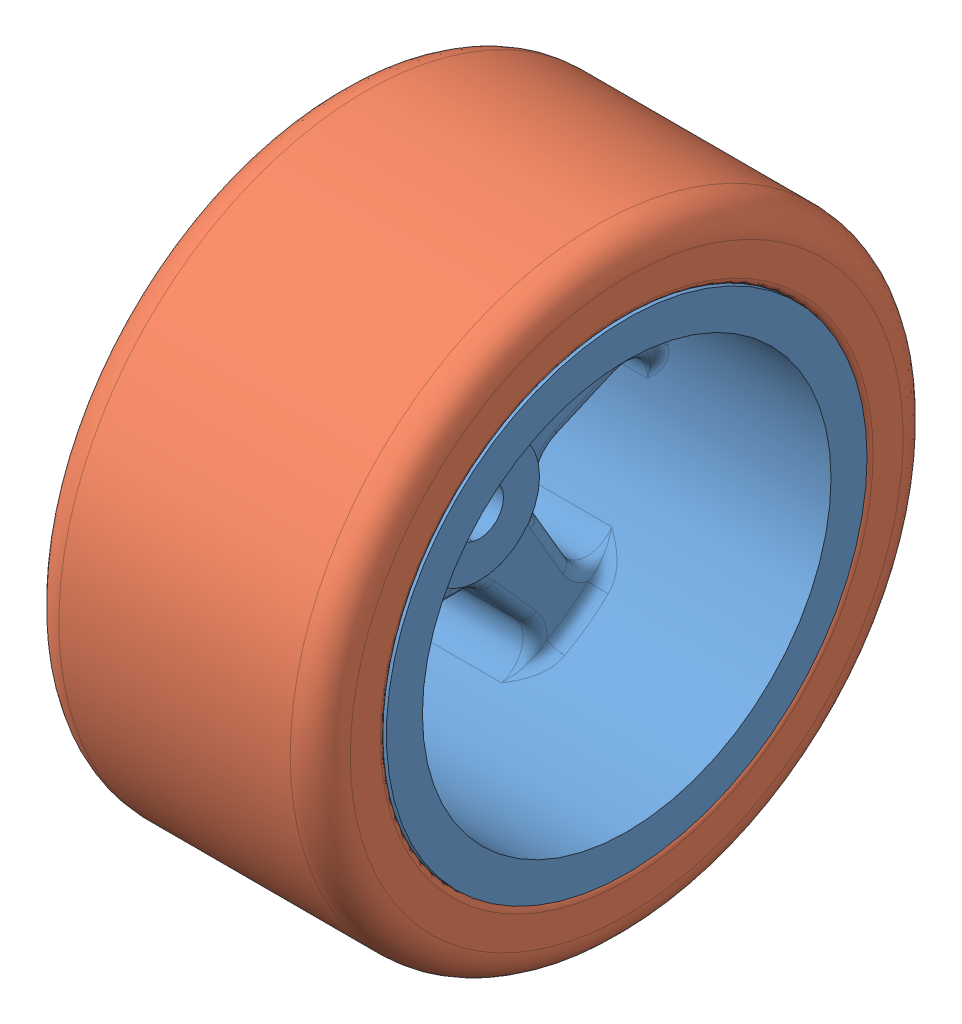
SolidWorks assembly _chassis_wheel_front, configuration Default. Lengths in mm.
Overall size (24.25 51 51).
2 component instances, 2 part files, 2 mates.
Components (placement in the parent):
- chassis_wheel_center_front-1: chassis_wheel_center_front [Default] at (5.9936 1.7491 -4.3511) size (24.25 40 40)
- chassis_tire-1: chassis_tire [Default] at (18.1186 1.7491 -4.3511) size (24.25 51 51)
Mates (geometry in assembly coordinates):
- Concentric1: concentric anti-aligned: cylinder of chassis_wheel_center_front-1 through (17.9936 1.7491 -4.3511) axis (1 0 0) radius 19; cylinder of chassis_tire-1 through (18.1186 1.7491 -4.3511) axis (-1 0 0) radius 19
- Coincident1: coincident anti-aligned: plane of chassis_wheel_center_front-1 through (28.2436 1.7491 -24.3511) normal (-1 0 0); plane of chassis_tire-1 through (28.2436 1.7491 -23.3511) normal (1 0 0)
